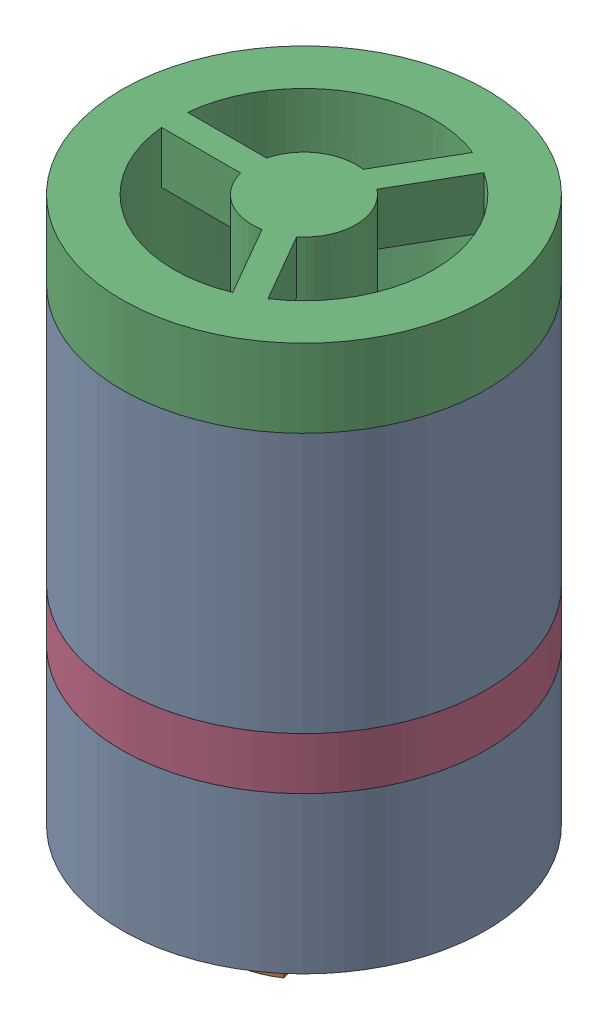
SolidWorks assembly Check valve_4, configuration 默认. Lengths in mm.
Overall size (14 24 14).
4 component instances, 4 part files, 0 mates.
Components (placement in the parent):
- Check valve housing-1: Check valve housing [默认] at origin size (14 18 14)
- Valve-1: Valve [默认] at (0 5 0) x (0.259222 0 0.965818) z (0.965818 0 -0.259222) size (8 11 8)
- Valve lock-1: Valve lock [默认] at (0 13 0) size (14 8 14)
- Seal-1: Seal [默认] at (0 6 0) size (14 2 14)
